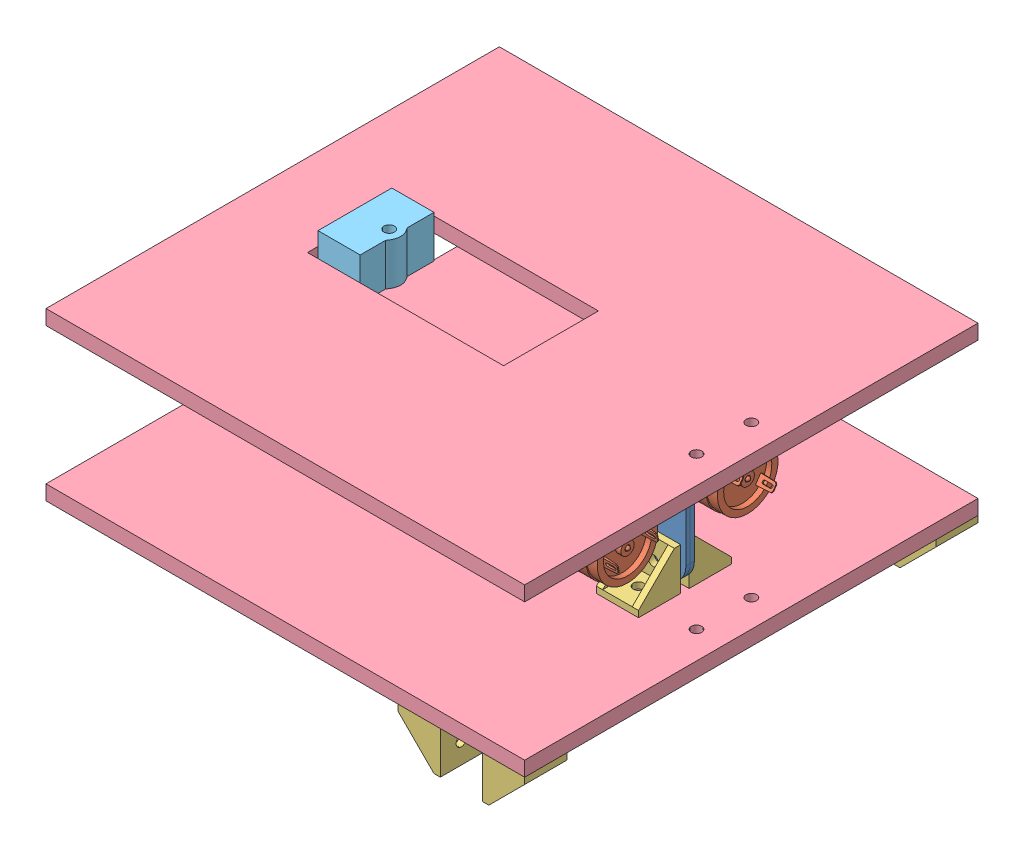
SolidWorks assembly CLAW ASSEM, configuration Default. Lengths in mm.
Overall size (227 105.5 215).
16 component instances, 5 part files, 47 mates.
Components (placement in the parent):
- MOTOR CLAMP-1: MOTOR CLAMP [Default] at (18.8124 38.0248 53.9381) size (68 60 57)
- MOTOR CLAMP-2: MOTOR CLAMP [Default] at (18.8124 38.0248 53.9381) x (1 0 0) z (0 0 -1) size (68 60 57)
- IG-32GM_Geared_DC_Motor-1: IG-32GM_Geared_DC_Motor [Default] at (46.6124 38.0248 25.4381) x (0 -0.561541 -0.827449) z (0 0.827449 -0.561541) size (32.25 89.06 32.25)
- IG-32GM_Geared_DC_Motor-2: IG-32GM_Geared_DC_Motor [Default] at (46.6124 38.0248 82.4381) x (0 -0.188025 0.982164) z (0 -0.982164 -0.188025) size (32.25 89.06 32.25)
- 2020CornerBracket.step-1: 2020CornerBracket.step [Default] at (50.3124 5.5248 55.9381) size (20 20 20)
- 2020CornerBracket.step-2: 2020CornerBracket.step [Default] at (30.3124 5.5248 51.9381) x (-1 0 0) z (0 0 -1) size (20 20 20)
- 2020CornerBracket.step-3: 2020CornerBracket.step [Default] at (30.3124 70.5248 55.9381) x (-1 0 0) z (0 0 1) size (20 20 20)
- 2020CornerBracket.step-4: 2020CornerBracket.step [Default] at (50.3124 70.5248 51.9381) x (1 0 0) z (0 0 -1) size (20 20 20)
- CLAW BASE-1: CLAW BASE [Default] at (-28.5983 -1.4752 53.9381) x (0 0 -1) z (0 1 0) size (215 227 7)
- S PART 3-1: S PART 3 [Default] at (-89.933 -7.9752 53.011) x (0 0 1) z (-1 0 0) size (35 20 22.01)
- CLAW BASE-2: CLAW BASE [Default] at (-28.5983 77.5248 53.9381) x (0 0 1) z (0 -1 0) size (215 227 7)
- S PART 3-2: S PART 3 [Default] at (-89.933 64.0248 53.011) x (0 0 1) z (-1 0 0) size (35 20 22.01)
- 2020CornerBracket.step-5: 2020CornerBracket.step [Default] at (41.8124 -1.4752 141.4381) x (0 0 -1) z (-1 0 0) size (20 20 20)
- 2020CornerBracket.step-6: 2020CornerBracket.step [Default] at (41.8124 -1.4752 -53.5619) x (0 0 -1) z (-1 0 0) size (20 20 20)
- 2020CornerBracket.step-7: 2020CornerBracket.step [Default] at (61.8124 -1.4752 161.4381) x (0 0 1) z (1 0 0) size (20 20 20)
- 2020CornerBracket.step-8: 2020CornerBracket.step [Default] at (61.8124 -1.4752 -53.5619) x (0 0 -1) z (0 -1 0) size (20 20 20)
Mates (geometry in assembly coordinates):
- Coincident1: coincident anti-aligned: plane of MOTOR CLAMP-1 through (42.8124 58.0248 53.9381) normal (0 0 -1); plane of MOTOR CLAMP-2 through (42.8124 18.0248 53.9381) normal (0 0 1)
- Coincident2: coincident aligned: plane of MOTOR CLAMP-1 through (-15.1876 8.0248 55.9381) normal (-1 0 0); plane of MOTOR CLAMP-2 through (-15.1876 68.0248 51.9381) normal (-1 0 0)
- Concentric1: concentric anti-aligned: cylinder of MOTOR CLAMP-1 through (40.3124 60.5248 0.9381) axis (0 0 1) radius 2.5853; cylinder of MOTOR CLAMP-2 through (40.3124 60.5248 106.9381) axis (0 0 -1) radius 2.5853
- Coincident3: coincident anti-aligned: plane of MOTOR CLAMP-2 through (-13.1876 8.0248 -3.0619) normal (1 0 0); plane of IG-32GM_Geared_DC_Motor-1 through (-13.1876 38.0248 25.4381) normal (-1 0 0)
- Concentric2: concentric anti-aligned: cylinder of MOTOR CLAMP-2 through (39.8124 38.0248 25.4381) axis (-1 0 0) radius 10; cylinder of IG-32GM_Geared_DC_Motor-1 through (-16.1876 38.0248 25.4381) axis (1 0 0) radius 10
- Tangent1: tangent: cylinder of MOTOR CLAMP-2 through (39.8124 49.8028 25.4381) axis (-1 0 0) radius 1; cylinder of IG-32GM_Geared_DC_Motor-1 through (-7.6876 50.5258 27.8312) axis (-1 0 0) radius 1.5
- Coincident4: coincident: plane of MOTOR CLAMP-1 through (-13.1876 68.0248 110.9381) normal (1 0 0); plane of IG-32GM_Geared_DC_Motor-2 through (-13.1876 38.0248 82.4381) normal (-1 0 0)
- Concentric4: concentric: cylinder of MOTOR CLAMP-1 through (39.8124 38.0248 82.4381) axis (-1 0 0) radius 10; cylinder of IG-32GM_Geared_DC_Motor-2 through (-16.1876 38.0248 82.4381) axis (1 0 0) radius 10
- Tangent3: tangent: cylinder of MOTOR CLAMP-1 through (39.8124 29.6966 90.7663) axis (-1 0 0) radius 1; cylinder of IG-32GM_Geared_DC_Motor-2 through (-7.6876 27.4931 89.5853) axis (-1 0 0) radius 1.5
- Concentric7: concentric anti-aligned: cylinder of MOTOR CLAMP-1 through (40.3124 15.5248 0.9381) axis (0 0 1) radius 2.5853; cylinder of 2020CornerBracket.step-1 through (40.3124 15.5248 75.9381) axis (0 0 -1) radius 2.5
- Coincident5: coincident anti-aligned: plane of MOTOR CLAMP-1 through (42.8124 58.0248 55.9381) normal (0 0 1); plane of 2020CornerBracket.step-1 through (50.3124 5.5248 55.9381) normal (0 0 -1)
- Parallel4: parallel aligned: plane of MOTOR CLAMP-1 through (-15.1876 8.0248 55.9381) normal (0 -1 0); plane of 2020CornerBracket.step-1 through (40.3124 5.5248 65.9381) normal (0 -1 0)
- Coincident7: coincident anti-aligned: plane of MOTOR CLAMP-2 through (42.8124 18.0248 51.9381) normal (0 0 -1); plane of 2020CornerBracket.step-2 through (30.3124 5.5248 51.9381) normal (0 0 1)
- Concentric8: concentric: cylinder of MOTOR CLAMP-2 through (40.3124 15.5248 106.9381) axis (0 0 -1) radius 2.5853; cylinder of 2020CornerBracket.step-2 through (40.3124 15.5248 31.9381) axis (0 0 1) radius 2.5
- Parallel5: parallel aligned: plane of MOTOR CLAMP-2 through (-15.1876 8.0248 51.9381) normal (0 -1 0); plane of 2020CornerBracket.step-2 through (40.3124 5.5248 41.9381) normal (0 -1 0)
- Coincident9: coincident anti-aligned: plane of MOTOR CLAMP-1 through (42.8124 58.0248 55.9381) normal (0 0 1); plane of 2020CornerBracket.step-3 through (30.3124 70.5248 55.9381) normal (0 0 -1)
- Coincident11: coincident: plane of MOTOR CLAMP-2 through (42.8124 18.0248 51.9381) normal (0 0 -1); plane of 2020CornerBracket.step-4 through (50.3124 70.5248 51.9381) normal (0 0 1)
- Concentric9: concentric: cylinder of MOTOR CLAMP-1 through (40.3124 60.5248 0.9381) axis (0 0 1) radius 2.5853; cylinder of 2020CornerBracket.step-3 through (40.3124 60.5248 75.9381) axis (0 0 -1) radius 2.5
- Concentric10: concentric: cylinder of MOTOR CLAMP-2 through (40.3124 60.5248 106.9381) axis (0 0 -1) radius 2.5853; cylinder of 2020CornerBracket.step-4 through (40.3124 60.5248 31.9381) axis (0 0 1) radius 2.5
- Parallel6: parallel aligned: plane of MOTOR CLAMP-2 through (-15.1876 68.0248 51.9381) normal (0 1 0); plane of 2020CornerBracket.step-4 through (40.3124 70.5248 41.9381) normal (0 1 0)
- Parallel7: parallel aligned: plane of MOTOR CLAMP-1 through (-15.1876 68.0248 55.9381) normal (0 1 0); plane of 2020CornerBracket.step-3 through (40.3124 70.5248 65.9381) normal (0 1 0)
- Coincident12: coincident anti-aligned: plane of 2020CornerBracket.step-1 through (40.3124 5.5248 65.9381) normal (0 -1 0); plane of CLAW BASE-1 through (-28.5983 5.5248 53.9381) normal (0 1 0)
- Width1: width anti-aligned: plane of CLAW BASE-1 through (-28.5983 5.5248 161.4381) normal (0 0 1); plane of 2020CornerBracket.step-2 through (-28.5983 5.5248 -53.5619) normal (0 0 -1); plane of CLAW BASE-1 through (50.3124 5.5248 31.9381) normal (0 0 -1); plane of 2020CornerBracket.step-1 through (30.3124 5.5248 75.9381) normal (0 0 1)
- Width2: width anti-aligned: plane of CLAW BASE-1 through (-28.5983 5.5248 161.4381) normal (0 0 1); plane of MOTOR CLAMP-2 through (-28.5983 5.5248 -53.5619) normal (0 0 -1); plane of CLAW BASE-1 through (42.8124 18.0248 51.9381) normal (0 0 -1); plane of MOTOR CLAMP-1 through (42.8124 58.0248 55.9381) normal (0 0 1)
- Distance2: distance = 95 mm aligned: plane of MOTOR CLAMP-2 through (-13.1876 8.0248 -3.0619) normal (1 0 0); plane of CLAW BASE-1 through (81.8124 5.5248 53.9381) normal (1 0 0)
- Coincident15: coincident anti-aligned: plane of CLAW BASE-1 through (-106.1876 5.5248 53.9381) normal (1 0 0); plane of S PART 3-1 through (-106.1876 12.0248 36.4381) normal (-1 0 0)
- Coincident16: coincident anti-aligned: plane of CLAW BASE-1 through (-106.1876 5.5248 53.9381) normal (1 0 0); plane of S PART 3-1 through (-106.1876 12.0248 36.4381) normal (-1 0 0)
- Width3: width aligned: plane of CLAW BASE-1 through (-28.5983 5.5248 76.4381) normal (0 0 -1); plane of S PART 3-1 through (-28.5983 5.5248 31.4381) normal (0 0 1); plane of CLAW BASE-1 through (-86.1876 12.0248 36.4381) normal (0 0 -1); plane of S PART 3-1 through (-106.1876 12.0248 71.4381) normal (0 0 1)
- Coincident17: coincident anti-aligned: plane of 2020CornerBracket.step-4 through (40.3124 70.5248 41.9381) normal (0 1 0); plane of CLAW BASE-2 through (-28.5983 70.5248 53.9381) normal (0 -1 0)
- Coincident19: coincident aligned: plane of CLAW BASE-1 through (-28.5983 5.5248 -53.5619) normal (0 0 -1); plane of CLAW BASE-2 through (-28.5983 70.5248 -53.5619) normal (0 0 -1)
- Concentric11: concentric anti-aligned: cylinder of CLAW BASE-1 through (68.8124 5.5248 40.9381) axis (0 -1 0) radius 2.5; cylinder of CLAW BASE-2 through (68.8124 70.5248 40.9381) axis (0 1 0) radius 2.5
- Coincident20: coincident anti-aligned: plane of CLAW BASE-2 through (-106.1876 70.5248 53.9381) normal (1 0 0); plane of S PART 3-2 through (-106.1876 84.0248 36.4381) normal (-1 0 0)
- Concentric12: concentric: cylinder of S PART 3-1 through (-89.933 12.0248 53.9381) axis (0 -1 0) radius 2.5; cylinder of S PART 3-2 through (-89.933 84.0248 53.9381) axis (0 -1 0) radius 2.5
- Coincident21: coincident: plane of CLAW BASE-2 through (-106.1876 70.5248 53.9381) normal (1 0 0); plane of S PART 3-2 through (-106.1876 84.0248 36.4381) normal (-1 0 0)
- Width4: width aligned: plane of CLAW BASE-2 through (-28.5983 70.5248 31.4381) normal (0 0 1); plane of CLAW BASE-2 through (-28.5983 70.5248 76.4381) normal (0 0 -1); plane of S PART 3-2 through (-106.1876 84.0248 71.4381) normal (0 0 1); plane of S PART 3-2 through (-86.1876 84.0248 36.4381) normal (0 0 -1)
- Width5: width anti-aligned: plane of S PART 3-2 through (-84.1772 84.0248 54.2593) normal (0 1 0); plane of S PART 3-2 through (-84.1772 64.0248 54.2593) normal (0 -1 0); plane of CLAW BASE-2 through (-28.5983 70.5248 53.9381) normal (0 -1 0); plane of CLAW BASE-2 through (-28.5983 77.5248 53.9381) normal (0 1 0)
- Width6: width: plane of S PART 3-1 through (-84.1772 -7.9752 54.2593) normal (0 -1 0); plane of S PART 3-1 through (-84.1772 12.0248 54.2593) normal (0 1 0); plane of CLAW BASE-1 through (-28.5983 5.5248 53.9381) normal (0 1 0); plane of CLAW BASE-1 through (-28.5983 -1.4752 53.9381) normal (0 -1 0)
- Coincident44: coincident anti-aligned: plane of CLAW BASE-1 through (-28.5983 -1.4752 53.9381) normal (0 -1 0); plane of 2020CornerBracket.step-5 through (31.8124 -1.4752 151.4381) normal (0 1 0)
- Coincident45: coincident anti-aligned: plane of CLAW BASE-1 through (-28.5983 -1.4752 53.9381) normal (0 -1 0); plane of 2020CornerBracket.step-8 through (61.8124 -1.4752 -53.5619) normal (0 1 0)
- Coincident46: coincident anti-aligned: plane of CLAW BASE-1 through (-28.5983 -1.4752 53.9381) normal (0 -1 0); plane of 2020CornerBracket.step-7 through (71.8124 -1.4752 151.4381) normal (0 1 0)
- Coincident47: coincident aligned: plane of CLAW BASE-1 through (-28.5983 5.5248 161.4381) normal (0 0 1); plane of 2020CornerBracket.step-7 through (81.8124 -1.4752 161.4381) normal (0 0 1)
- Coincident48: coincident aligned: plane of CLAW BASE-1 through (-28.5983 5.5248 -53.5619) normal (0 0 -1); plane of 2020CornerBracket.step-8 through (61.8124 -21.4752 -53.5619) normal (0 0 -1)
- Coincident50: coincident anti-aligned: plane of CLAW BASE-1 through (-28.5983 -1.4752 53.9381) normal (0 -1 0); plane of 2020CornerBracket.step-6 through (31.8124 -1.4752 -43.5619) normal (0 1 0)
- Coincident55: coincident aligned: plane of CLAW BASE-1 through (81.8124 5.5248 53.9381) normal (1 0 0); plane of 2020CornerBracket.step-8 through (81.8124 -11.4752 -43.5619) normal (1 0 0)
- Coincident56: coincident aligned: plane of CLAW BASE-1 through (81.8124 5.5248 53.9381) normal (1 0 0); plane of 2020CornerBracket.step-7 through (81.8124 -1.4752 141.4381) normal (1 0 0)
- Coincident61: coincident aligned: plane of CLAW BASE-1 through (-28.5983 5.5248 -53.5619) normal (0 0 -1); plane of 2020CornerBracket.step-6 through (21.8124 -1.4752 -53.5619) normal (0 0 -1)
- Coincident63: coincident aligned: plane of CLAW BASE-1 through (-28.5983 5.5248 161.4381) normal (0 0 1); plane of 2020CornerBracket.step-5 through (41.8124 -1.4752 161.4381) normal (0 0 1)
